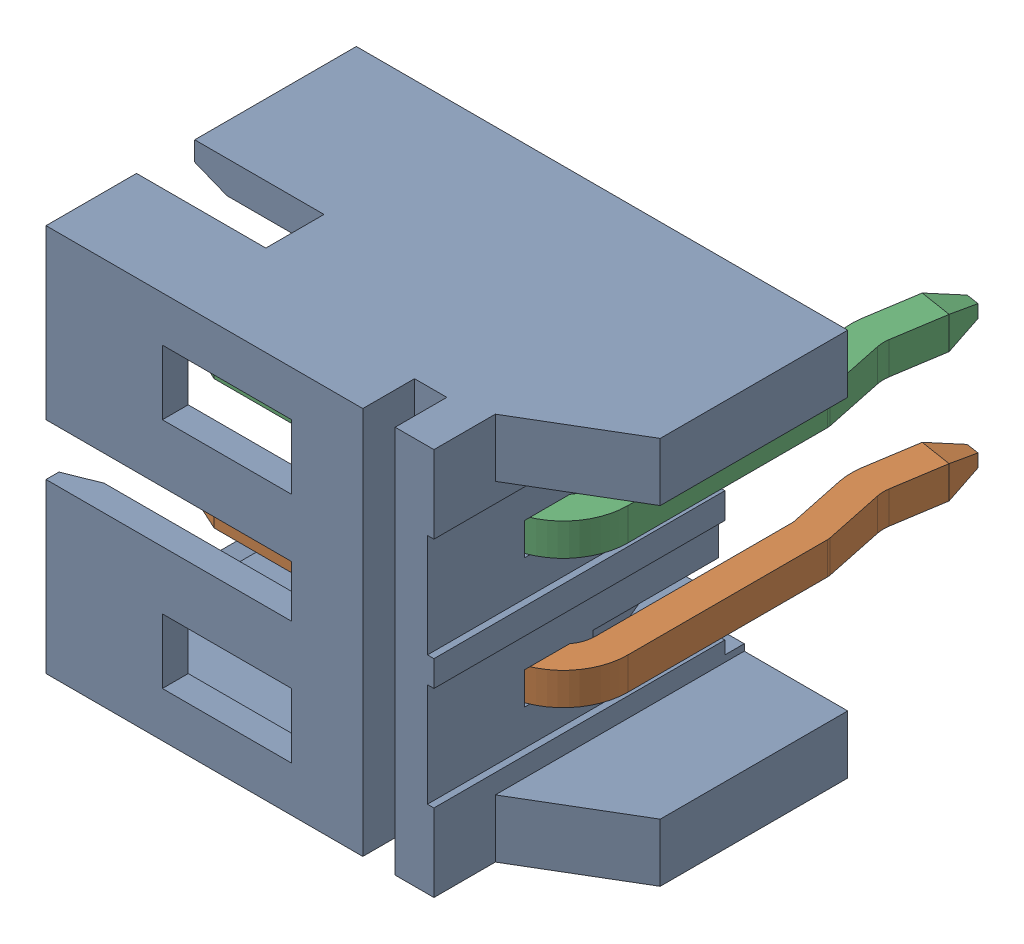
SolidWorks assembly J4, configuration Default. Lengths in mm.
Overall size (7.6 6 8.09).
4 component instances, 2 part files, 0 mates.
Components (placement in the parent):
- 62000211722-1: 62000211722 [Default] at (0.2161 9.8799 2.45) x (0 1 0) z (-1 0 0) size (6 8.09 7.6)
  - 62000211722-1: 62000211722 [Default] at origin size (6 4.8 7.6)
  - 6200xx11722_PIN1-1: 6200xx11722_PIN1 [Default] at (-1 1.645 -0.05) size (0.5 6.59 5.9)
  - 6200xx11722_PIN1-2: 6200xx11722_PIN1 [Default] at (1 1.645 -0.05) size (0.5 6.59 5.9)
